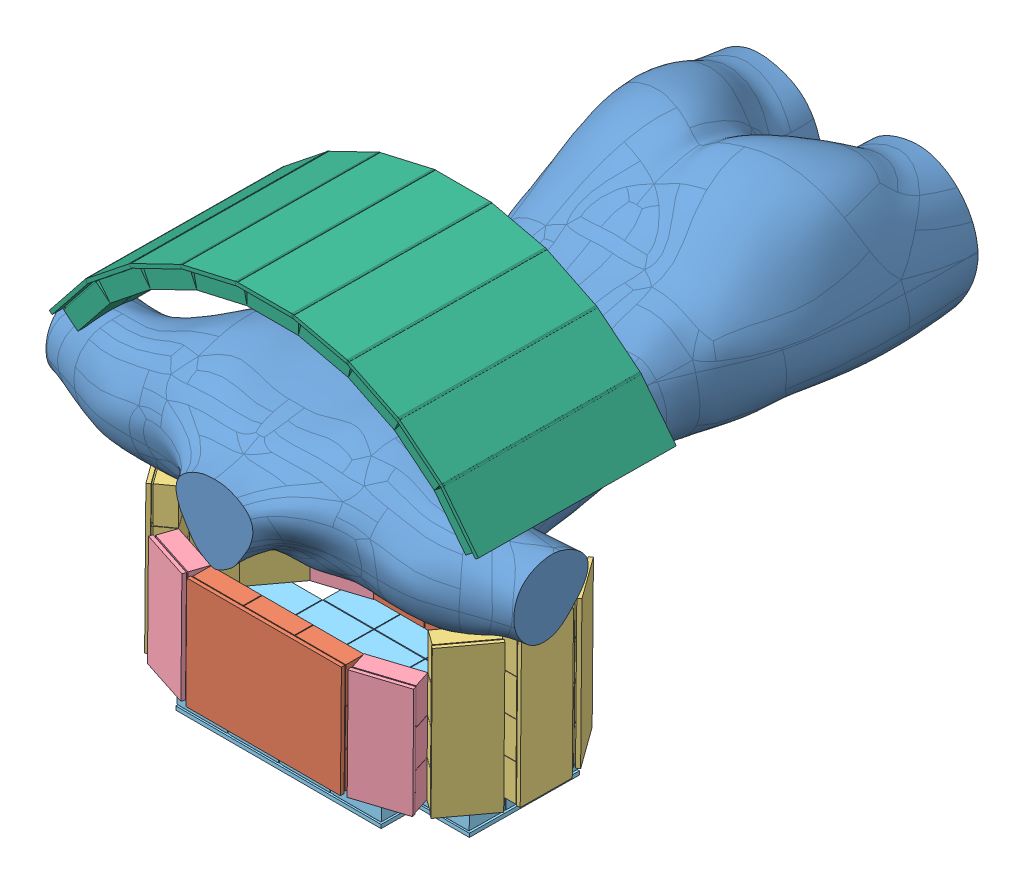
SolidWorks assembly Assem1, configuration Default. Lengths in mm.
Overall size (701.61 770.29 899.3).
28 component instances, 6 part files, 2 mates.
Components (placement in the parent):
- woman body-1: woman body [Default] at (196.8565 656.3794 482.852) size (701.61 331.12 899.3)
- Detector1n3_4-1: Detector1n3_4 [Default] at (227.8579 476.9138 1063.4621) x (1 0 0) z (0 -0.999962 0.008727) size (565.24 340.33 232)
  - Detector1n2_3_changed-1: Detector1n2_3_changed [Default] at (-17.8211 -202.8407 225.44) size (565.24 340.33 201.48)
    - top_bottomDetector3-2: top_bottomDetector3 [Default] at (-106.7647 78.2438 -235.0736) size (211 32 151.22)
    - CshapedDetector2-3: CshapedDetector2 [Default] at (62.2764 -58.5479 -394.5758) x (0.951057 0.309017 0) z (0 0 1) size (177.89 270.84 200)
      - 1Detector-2: 1Detector [Default] at (173.0714 153.2337 184.2598) x (0.809017 0.587785 0) z (0 0 1) size (71 32 200)
      - 1Detector-4: 1Detector [Default] at (223.2683 222.3237 184.2598) x (0.309017 0.951057 0) z (0 0 1) size (71 32 200)
      - 1Detector-5: 1Detector [Default] at (223.2683 307.7237 184.2598) x (-0.309017 0.951057 0) z (0 0 1) size (71 32 200)
      - 1Detector_3modules-1: 1Detector_3modules [Default] at (91.8512 126.8436 209.2598) size (71 32 150)
      - 1Detector_3modules-2: 1Detector_3modules [Default] at (173.0714 376.8138 209.2598) x (-0.809017 0.587785 0) z (0 0 1) size (71 32 150)
    - CshapedDetector2-4: CshapedDetector2 [Default] at (-135.8058 502.3243 -394.5758) x (-0.951057 -0.309017 0) z (0 0 1) size (177.89 270.84 200)
      - 1Detector-2: 1Detector [Default] at (173.0714 153.2337 184.2598) x (0.809017 0.587785 0) z (0 0 1) size (71 32 200)
      - 1Detector-4: 1Detector [Default] at (223.2683 222.3237 184.2598) x (0.309017 0.951057 0) z (0 0 1) size (71 32 200)
      - 1Detector-5: 1Detector [Default] at (223.2683 307.7237 184.2598) x (-0.309017 0.951057 0) z (0 0 1) size (71 32 200)
      - 1Detector_3modules-1: 1Detector_3modules [Default] at (91.8512 126.8436 209.2598) size (71 32 150)
      - 1Detector_3modules-2: 1Detector_3modules [Default] at (173.0714 376.8138 209.2598) x (-0.809017 0.587785 0) z (0 0 1) size (71 32 150)
    - top_bottomDetector3-3: top_bottomDetector3 [Default] at (-106.7647 365.5325 -135.0585) x (1 0 0) z (0 0 -1) size (211 32 151.22)
  - bottomDetector-1: bottomDetector [Default] at (-228.4057 17.9076 147.124) x (1 0 0) z (0 1 0) size (421 32 250)
- CshapedDetector1-2: CshapedDetector1 [Default] at (457.513 931.4813 902.9213) x (-0.900926 0.433957 -0.003787) z (0 0.008727 0.999962) size (527.59 312.86 270)
  - 5Detector-1: 5Detector [Default] at (91.8512 126.8436 184.2598) size (80 32 270)
  - 5Detector-2: 5Detector [Default] at (168.0955 135.4362 184.2598) x (0.974917 0.22257 0) z (0 0 1) size (80 32 270)
  - 5Detector-4: 5Detector [Default] at (240.515 160.783 184.2598) x (0.900926 0.433974 0) z (0 0 1) size (80 32 270)
  - 5Detector-5: 5Detector [Default] at (305.4764 201.6123 184.2598) x (0.781738 0.623607 0) z (0 0 1) size (80 32 270)
  - 5Detector-6: 5Detector [Default] at (359.7211 255.8759 184.2598) x (0.623334 0.781956 0) z (0 0 1) size (80 32 270)
  - 5Detector-7: 5Detector [Default] at (400.5278 320.8517 184.2598) x (0.433659 0.901077 0) z (0 0 1) size (80 32 270)
  - 5Detector-8: 5Detector [Default] at (15.6069 135.4362 184.2598) x (0.974917 -0.22257 0) z (0 0 1) size (80 32 270)
  - 5Detector-9: 5Detector [Default] at (-56.8125 160.783 184.2598) x (0.900926 -0.433974 0) z (0 0 1) size (80 32 270)
  - 5Detector-10: 5Detector [Default] at (425.8492 393.2799 184.2598) x (0.222229 0.974994 0) z (0 0 1) size (80 32 270)
Mates (geometry in assembly coordinates):
- Parallel1: parallel aligned: plane of Detector1n3_4-1/Detector1n2_3_changed-1/top_bottomDetector3-2 through (103.2722 485.4598 938.7859) normal (0 -0.008727 -0.999962); plane of CshapedDetector1-2/5Detector-4 through (206.0513 859.5271 963.0718) normal (0 -0.008727 -0.999962)
- Coincident2: coincident aligned: plane of Detector1n3_4-1/Detector1n2_3_changed-1/top_bottomDetector3-3 through (103.2722 387.9555 1226.9365) normal (0 0.008727 0.999962); plane of CshapedDetector1-2/5Detector-4 through (211.0513 888.7927 1222.5657) normal (0 0.008727 0.999962)
